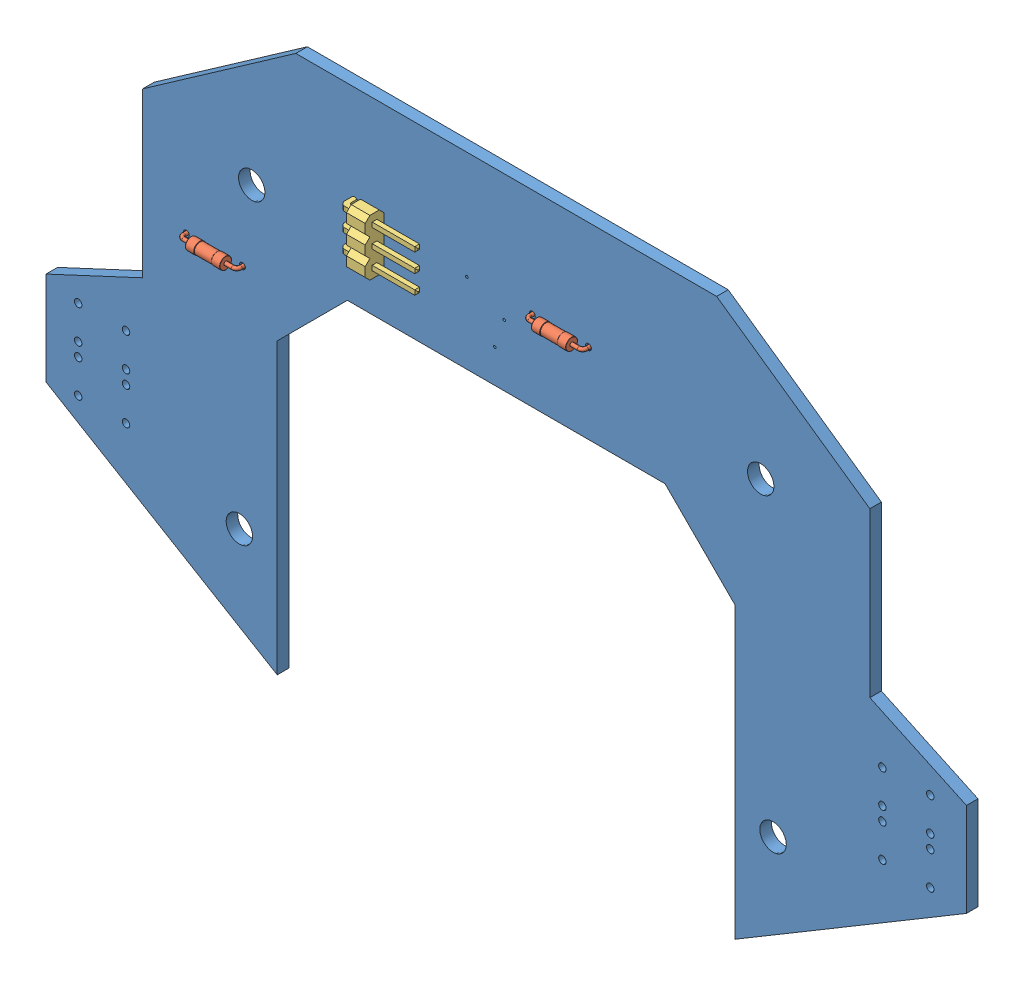
SolidWorks assembly PCB Component_1, configuration Default. Lengths in mm.
Overall size (125 74.35 5.54).
4 component instances, 3 part files, 0 mates.
Components (placement in the parent):
- Board_11-1: Board_11 [Default] at origin size (125 74.35 1.57)
- 0204-7_R11-1: 0204-7_R11 [Default] at (69.85 59.69 1.57) x (-1 0 0) z (0 0 1) size (8.2 1.6 3.52)
- 0204-7_R11-2: 0204-7_R11 [Default] at (22.86 45.72 1.57) size (8.2 1.6 3.52)
- 1X03-90_JP2-1: 1X03-90_JP2 [Default] at (45.72 58.42 1.57) x (0 -1 0) z (0 0 1) size (7.62 10.36 5.54)
